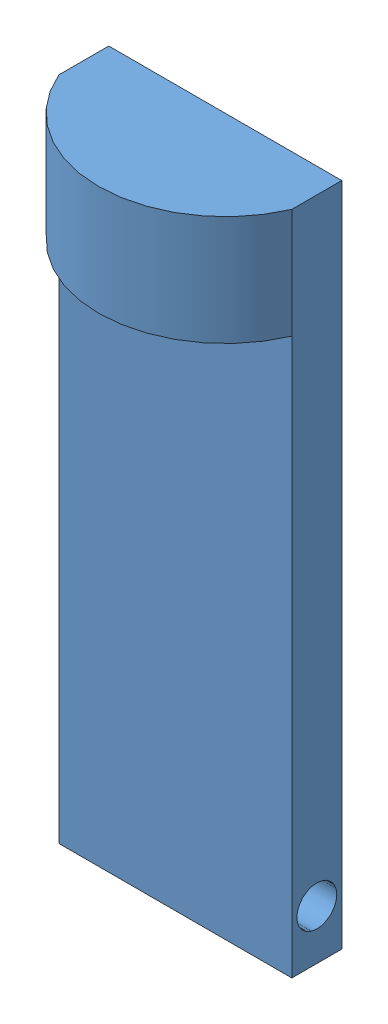
SolidWorks assembly forearm link, configuration Default. Lengths in mm.
Overall size (70 200 38.08).
2 component instances, 2 part files, 4 mates.
Components (placement in the parent):
- Part2-1: Part2 [Default] at (53.8642 102.313 158.3861) size (70 200 38.08)
- Part1^forearm link-1: Part1^forearm link [Default] at origin (virtual)
Mates (geometry in assembly coordinates):
- InPlace2: in place: plane of Part2-1 through (22.6142 202.313 173.3861) normal (0 1 0); plane of ? through (0 202.313 0) normal (0 1 0); moOrthogonalPlaneRef_w of Part2-1 through (22.6142 202.313 173.3861) normal (0 1 0); plane of ? through (0 202.313 0) normal (0 0 -1); plane of Part2-1 through (22.6142 202.313 173.3861) normal (0 1 0); plane of ? through (0 202.313 0) normal (1 0 0); plane of Part2-1 through (18.8642 202.313 173.3861) normal (0 1 0); unknown of ?
- Coincident4: coincident aligned: plane of Part2-1; plane of ?
- Coincident5: coincident aligned: moOrthogonalPlaneRef_w of Part2-1 through (53.8642 202.313 158.3861) normal (0 0 -1); plane of Part3^forearm link-1 through (53.8642 202.313 158.3861) normal (0 0 -1)
- Coincident6: coincident anti-aligned: moOrthogonalPlaneRef_w of Part2-1 through (53.8642 202.313 158.3861) normal (-1 0 0); plane of Part3^forearm link-1 through (53.8642 202.313 158.3861) normal (1 0 0)
